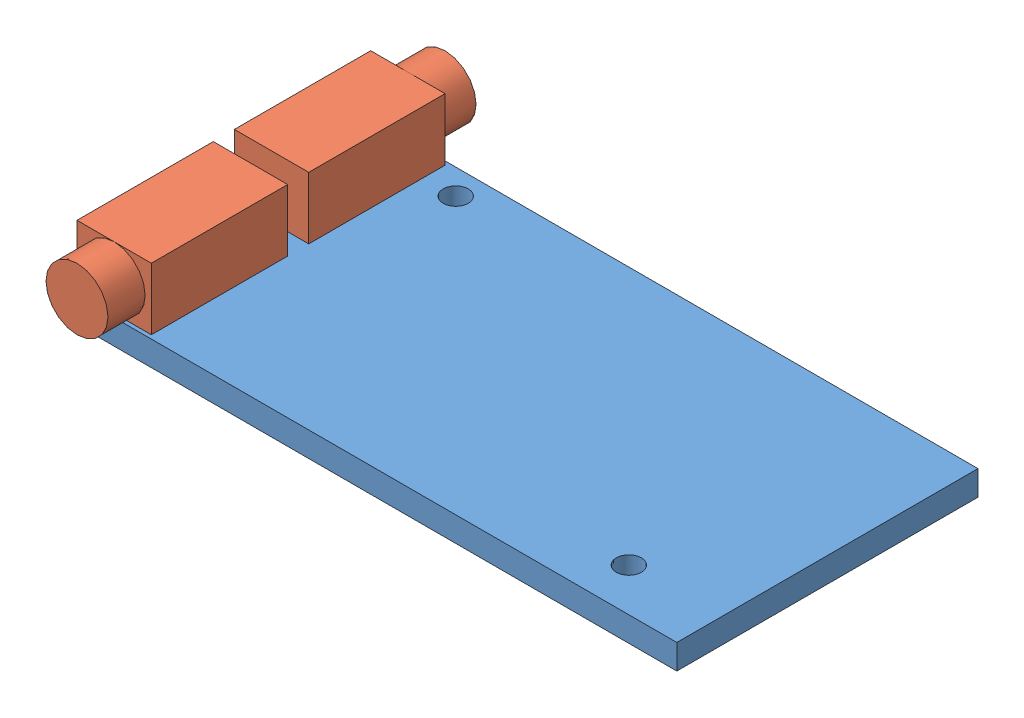
SolidWorks assembly _miniDSPV2, configuration Default. Lengths in mm.
Overall size (49 7.8 29.7).
3 component instances, 2 part files, 6 mates.
Components (placement in the parent):
- _miniDSPV2-1: _miniDSPV2 [Default] at (-8.5332 23.1601 27.6463) size (49 2 24.3)
- JACK-1: JACK [Default] at (-8.2332 25.1601 51.6463) x (0 0 -1) z (1 0 0) size (14 7.8 6)
- JACK-2: JACK [Default] at (-2.2332 25.1601 27.9463) x (0 0 1) z (-1 0 0) size (14 7.8 6)
Mates (geometry in assembly coordinates):
- Coincident1: coincident anti-aligned: plane of _miniDSPV2-1 through (-8.5332 25.1601 27.6463) normal (0 1 0); plane of JACK-1 through (-8.2332 25.1601 51.6463) normal (0 -1 0)
- Coincident2: coincident anti-aligned: plane of _miniDSPV2-1 through (-8.5332 25.1601 27.6463) normal (0 1 0); plane of JACK-2 through (-2.2332 25.1601 27.9463) normal (0 -1 0)
- Distance1: distance = 0.3 mm aligned: plane of JACK-1 through (-8.2332 30.1601 51.6463) normal (-1 0 0); plane of _miniDSPV2-1 through (-8.5332 25.1601 27.6463) normal (-1 0 0)
- Distance4: distance = 0.3 mm aligned: plane of JACK-2 through (-8.2332 30.1601 27.9463) normal (-1 0 0); plane of _miniDSPV2-1 through (-8.5332 25.1601 27.6463) normal (-1 0 0)
- Distance5: distance = 0.3 mm aligned: plane of JACK-1 through (-8.2332 30.1601 51.6463) normal (0 0 1); plane of _miniDSPV2-1 through (-8.5332 25.1601 51.9463) normal (0 0 1)
- Distance6: distance = 0.3 mm aligned: plane of _miniDSPV2-1 through (-8.5332 25.1601 27.6463) normal (0 0 -1); plane of JACK-2 through (-2.2332 30.1601 27.9463) normal (0 0 -1)
